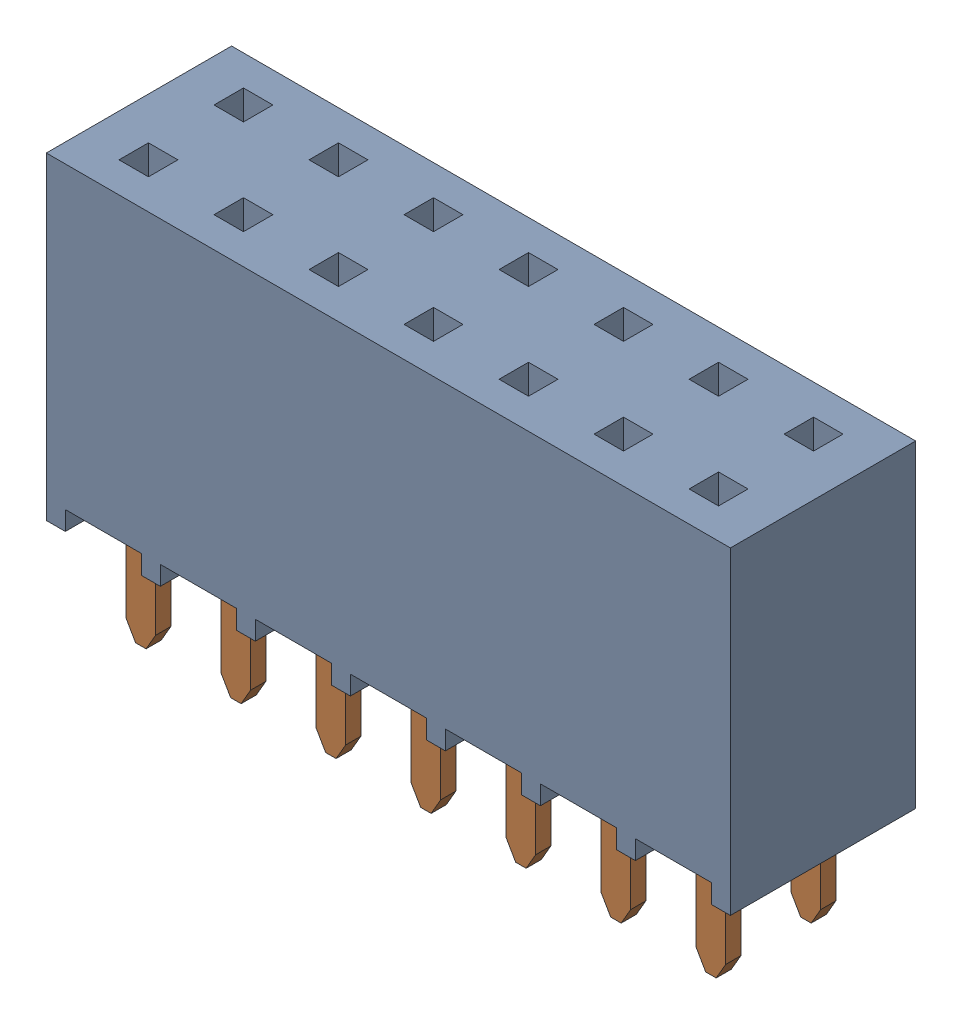
SolidWorks assembly SSW_107_01_L_D, configuration Default. Lengths in mm.
Overall size (18.29 11.15 4.95).
2 component instances, 2 part files, 0 mates.
Components (placement in the parent):
- _SSW_107_01_L_D_terminal_2-1: _SSW_107_01_L_D_terminal_2 [Default] at origin size (18.29 8.51 4.95)
- _SSW_107_01_L_D_pin_4-1: _SSW_107_01_L_D_pin_4 [Default] at (0 -2.6416 0) size (16.28 3.66 3.76)
